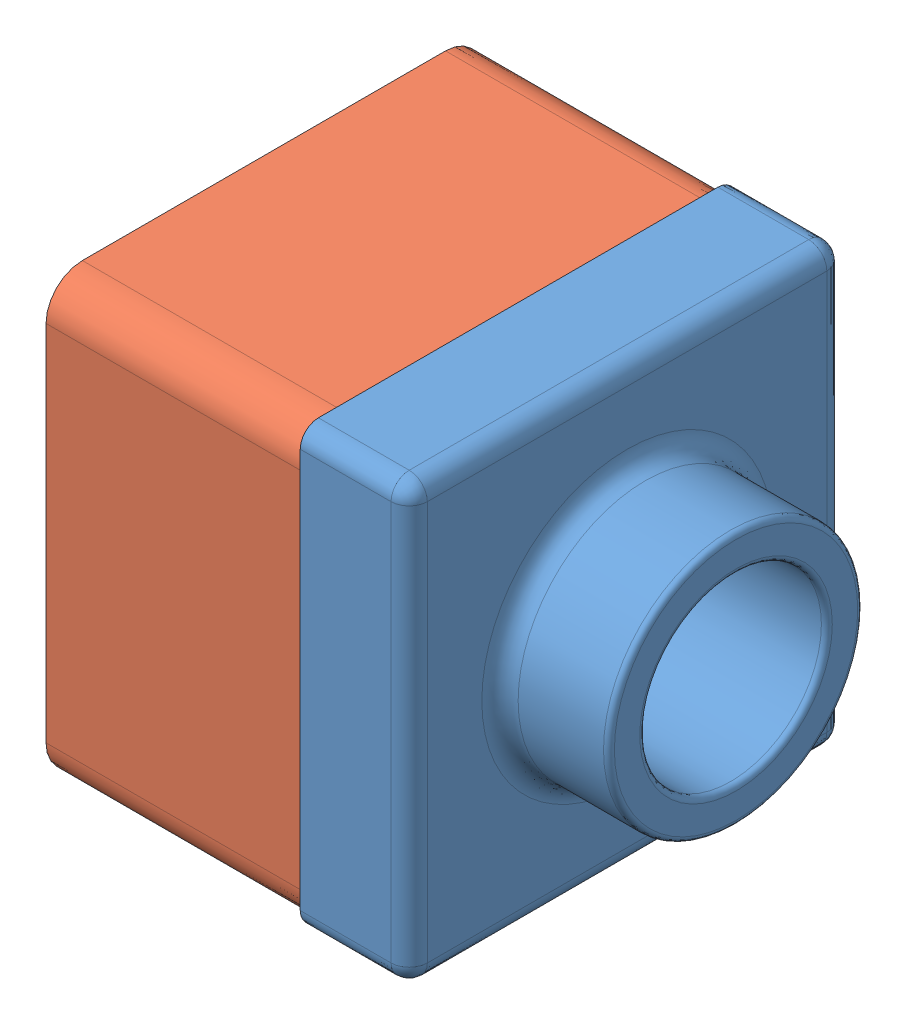
SolidWorks assembly Assem1, configuration Default. Lengths in mm.
Overall size (3302 3048 3048).
2 component instances, 2 part files, 3 mates.
Components (placement in the parent):
- Tutor1-1: Tutor1 [Default] at origin size (1524 3048 3048)
- Tutor2-1: Tutor2 [Default] at (-1778 -3048 -3048) x (0 0 1) z (1 0 0) size (3048 3048 2286)
Mates (geometry in assembly coordinates):
- Coincident10: coincident: plane of Tutor1-1 through (762 0 0) normal (0 0 1); plane of Tutor2-1 through (-98.0426 -3048 0) normal (0 0 1)
- Coincident11: coincident: plane of Tutor1-1 through (762 0 0) normal (0 1 0); plane of Tutor2-1 through (508 0 -3048) normal (0 1 0)
- Coincident12: coincident anti-aligned: plane of Tutor1-1 through (0 0 0) normal (-1 0 0); plane of Tutor2-1 through (0 -2794 -2794) normal (1 0 0)
